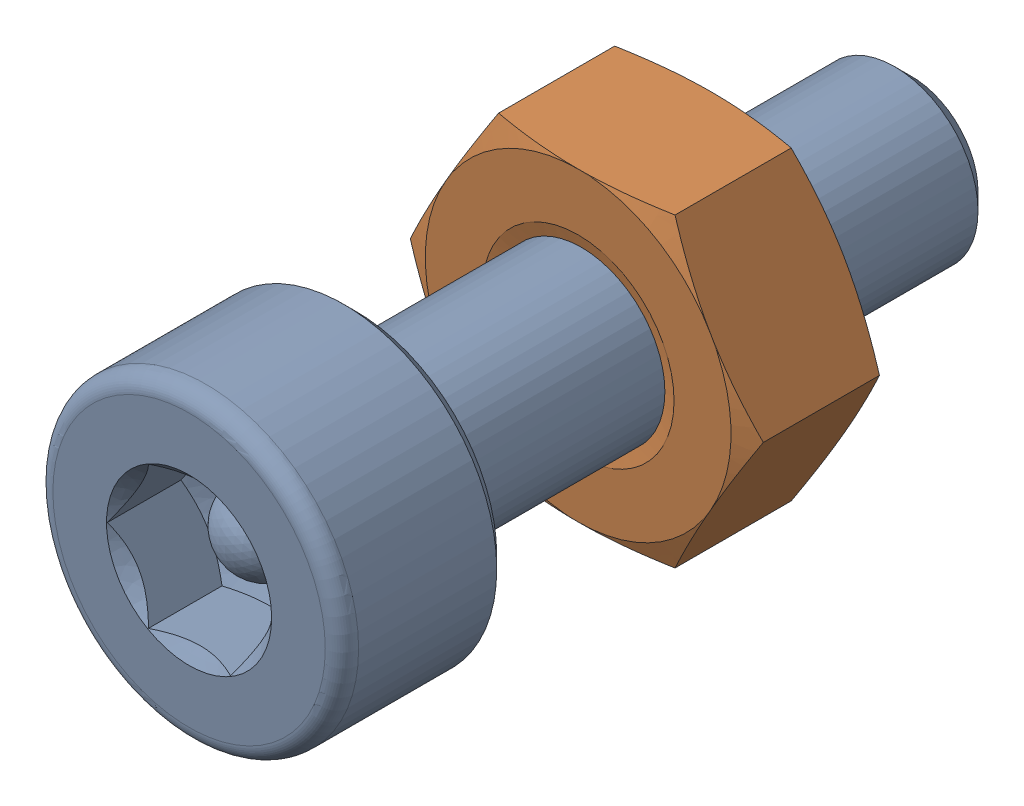
SolidWorks assembly Screw and Nut M3x010_015, configuration Varsayılan. Lengths in mm.
Overall size (6.35 5.5 13.14).
2 component instances, 2 part files, 0 mates.
Components (placement in the parent):
- M3x10-Screw014-1: M3x10-Screw014 [Varsayılan] at origin size (5.5 5.5 13.14)
- M3-Nut046-1: M3-Nut046 [Varsayılan] at (0 0 -4) x (-1 0 0) z (0 0 -1) size (6.35 5.5 2.4)
